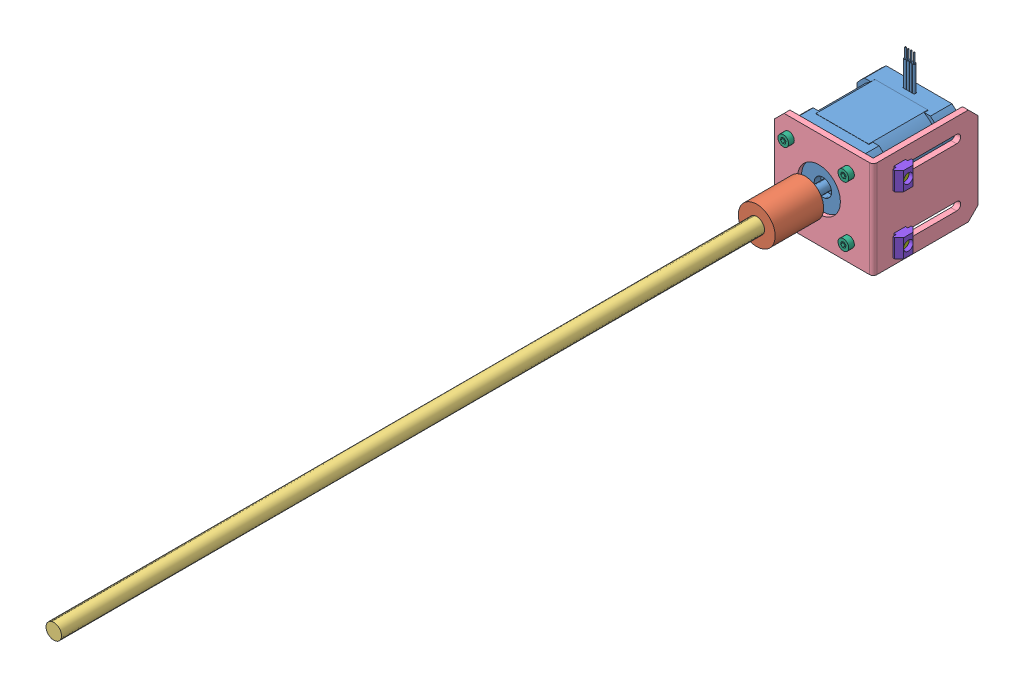
SolidWorks assembly 022Z轴活动机构-传动机构-1, configuration 默认. Lengths in mm.
Overall size (56.1 64 448.6).
16 component instances, 8 part files, 15 mates.
Components (placement in the parent):
- 42步进电机-1: 42步进电机 [默认] at (-11.8784 -10.5179 75.2) x (1 0 0) z (0 -1 0) size (42.2 71.2 60.1)
- 联轴器5X8-1: 联轴器5X8 [默认] at (-26.667 -18.0106 116.8) x (-1 0 0) z (0 0 -1) size (19 19 25)
- T8-2_375mm丝杆-导程2mm-1: T8-2_375mm丝杆-导程2mm [默认] at (-11.8784 -10.5179 106.8) size (8 8 375)
- 42电机支架-1: 42电机支架 [默认] at (-0.1697 -10.5179 87.2) x (0 -1 0) z (0 0 -1) size (50 51 54)
- M3_6_1尼龙垫片-1: M3_6_1尼龙垫片 [默认] at (-27.3784 4.9821 83.2) x (1 0 0) z (0 -1 0) size (6 1 6)
- M3_6_1尼龙垫片-2: M3_6_1尼龙垫片 [默认] at (3.6216 4.9821 83.2) x (1 0 0) z (0 -1 0) size (6 1 6)
- M3_6_1尼龙垫片-3: M3_6_1尼龙垫片 [默认] at (-27.3784 -26.0179 83.2) x (1 0 0) z (0 -1 0) size (6 1 6)
- M3_6_1尼龙垫片-4: M3_6_1尼龙垫片 [默认] at (3.6216 -26.0179 83.2) x (1 0 0) z (0 -1 0) size (6 1 6)
- M3_10-1: M3_10 [默认] at (-27.3784 4.9821 77.2) x (1 0 0) z (0 -1 0) size (5.5 12.93 5.5)
- M3_10-2: M3_10 [默认] at (3.6216 4.9821 77.2) x (1 0 0) z (0 -1 0) size (5.5 12.93 5.5)
- M3_10-3: M3_10 [默认] at (-27.3784 -26.0179 77.2) x (1 0 0) z (0 -1 0) size (5.5 12.93 5.5)
- M3_10-4: M3_10 [默认] at (3.6216 -26.0179 77.2) x (1 0 0) z (0 -1 0) size (5.5 12.93 5.5)
- M5_6-1: M5_6 [默认] at (19.1216 4.4821 74.2) x (0 1 0) z (0 0 1) size (8.5 10.91 8.5)
- 欧标20M5滑块螺母-1: 欧标20M5滑块螺母 [默认] at (21.2216 -0.2679 78.95) x (0 1 0) z (0 0 1) size (9.5 4.5 9.5)
- M5_6-2: M5_6 [默认] at (19.1216 -25.5179 74.2) x (0 1 0) z (0 0 1) size (8.5 10.91 8.5)
- 欧标20M5滑块螺母-2: 欧标20M5滑块螺母 [默认] at (21.2216 -30.2679 78.95) x (0 1 0) z (0 0 1) size (9.5 4.5 9.5)
Mates (geometry in assembly coordinates):
- 重合1: coincident: plane of 42步进电机-1 through (-11.8784 -10.5179 106.8) normal (0 0 1); plane of 联轴器5X8-1 through (-26.667 -18.0106 106.8) normal (0 0 -1)
- 同心1: concentric: circle of 42步进电机-1; axis of 联轴器5X8-1 through (-11.8784 -10.5179 94.3) axis (0 0 1)
- 重合2: coincident: plane of assembly; plane of assembly; plane of 联轴器5X8-1 through (-11.8784 -10.5179 106.8) normal (0 0 1); plane of T8-2_375mm丝杆-导程2mm-1 through (-11.8784 -10.5179 106.8) normal (0 0 -1)
- 同心2: concentric: cylinder of assembly; cylinder of assembly; cylinder of 联轴器5X8-1 through (-11.8784 -10.5179 119.3) axis (0 0 -1) radius 4; cylinder of T8-2_375mm丝杆-导程2mm-1 through (-11.8784 -10.5179 481.8) axis (0 0 -1) radius 4
- 同心3: concentric: cylinder of 42步进电机-1 through (-11.8784 -10.5179 85.2) axis (0 0 -1) radius 11; cylinder of 42电机支架-1 through (-11.8784 -10.5179 84.2) axis (0 0 1) radius 11.05
- 同心4: concentric: cylinder of 42步进电机-1 through (-27.3784 4.9821 83.2) axis (0 0 -1) radius 1.5; cylinder of 42电机支架-1 through (-27.3784 4.9821 84.2) axis (0 0 1) radius 1.75
- 同心5: concentric: cylinder of assembly; cylinder of assembly; cylinder of 42电机支架-1 through (-27.3784 4.9821 84.2) axis (0 0 1) radius 1.75; cylinder of M3_6_1尼龙垫片-1 through (-27.3784 4.9821 84.2) axis (0 0 -1) radius 1.5
- 重合4: coincident: plane of 42步进电机-1 through (-11.8784 -10.5179 83.2) normal (0 0 1); plane of M3_6_1尼龙垫片-1 through (-27.3784 4.9821 83.2) normal (0 0 -1)
- 重合5: coincident: plane of assembly; plane of assembly; plane of 42电机支架-1 through (-0.1697 -10.5179 84.2) normal (0 0 -1); plane of M3_6_1尼龙垫片-1 through (-27.3784 4.9821 84.2) normal (0 0 1)
- 重合6: coincident: plane of assembly; plane of assembly; plane of 42电机支架-1 through (-0.1697 -10.5179 87.2) normal (0 0 1); plane of M3_10-1 through (-27.3784 4.9821 87.2) normal (0 0 -1)
- 同心6: concentric: cylinder of 42步进电机-1 through (-27.3784 4.9821 83.2) axis (0 0 -1) radius 1.5; cylinder of M3_10-1 through (-27.3784 4.9821 87.2) axis (0 0 -1) radius 1.5
- 同心7: concentric: cylinder of assembly; cylinder of assembly; cylinder of M5_6-1 through (13.1216 4.4821 74.2) axis (1 0 0) radius 2.5; cylinder of 欧标20M5滑块螺母-1 through (21.2216 4.4821 74.2) axis (-1 0 0) radius 2.5
- 重合7: coincident: plane of assembly; plane of assembly; plane of 42电机支架-1 through (13.1216 14.4821 33.2) normal (-1 0 0); plane of M5_6-1 through (13.1216 4.4821 74.2) normal (1 0 0)
- 距离1: distance = 1.8 mm: plane of assembly; plane of assembly; plane of 欧标20M5滑块螺母-1 through (17.9216 -0.2679 78.95) normal (-1 0 0); plane of 42电机支架-1 through (16.1216 -35.5179 84.2) normal (1 0 0)
- 同心8: concentric: cylinder of assembly; cylinder of assembly; cylinder of 42电机支架-1 through (64.1216 4.4821 74.2) axis (-1 0 0) radius 2.1; cylinder of M5_6-1 through (13.1216 4.4821 74.2) axis (1 0 0) radius 2.5
